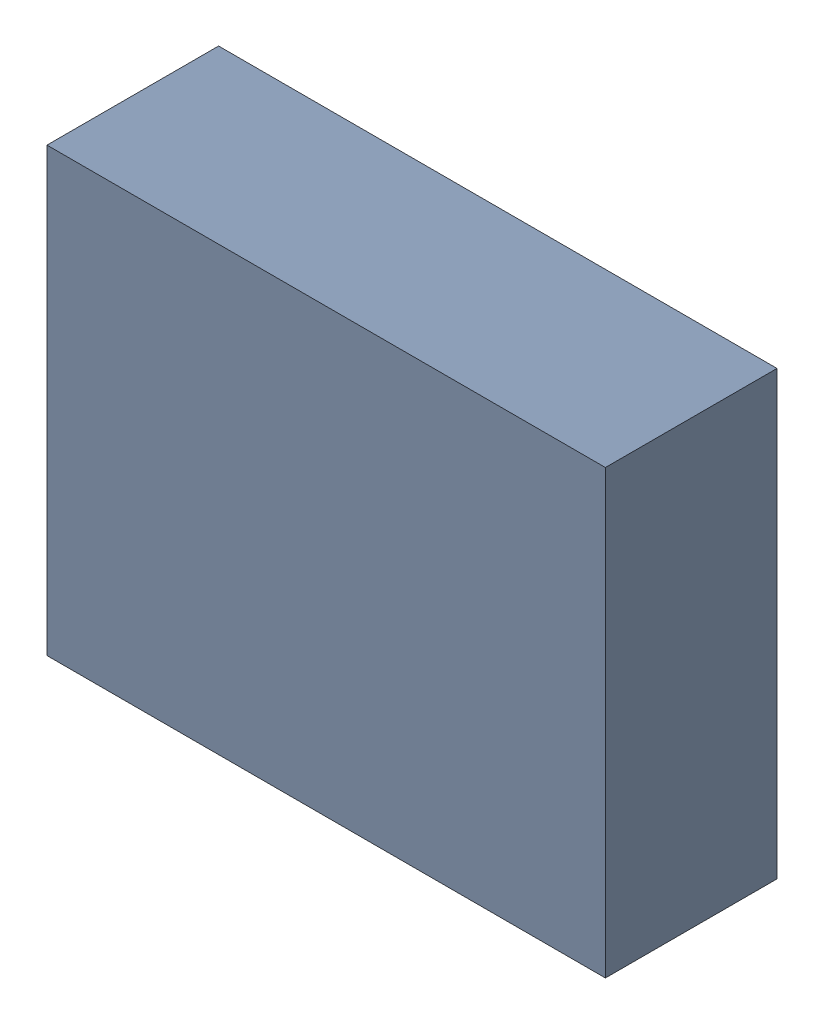
SolidWorks assembly OP5, configuration Default. Lengths in mm.
Overall size (5.04 3.99 1.55).
2 component instances, 1 part files, 0 mates.
Components (placement in the parent):
- 407985952-1: 407985952 [Default] at (35.814 22.733 0.2157) size (5.04 3.99 1.55)
  - Extruded-1: Extruded [Default] at origin size (5.04 3.99 1.55)
